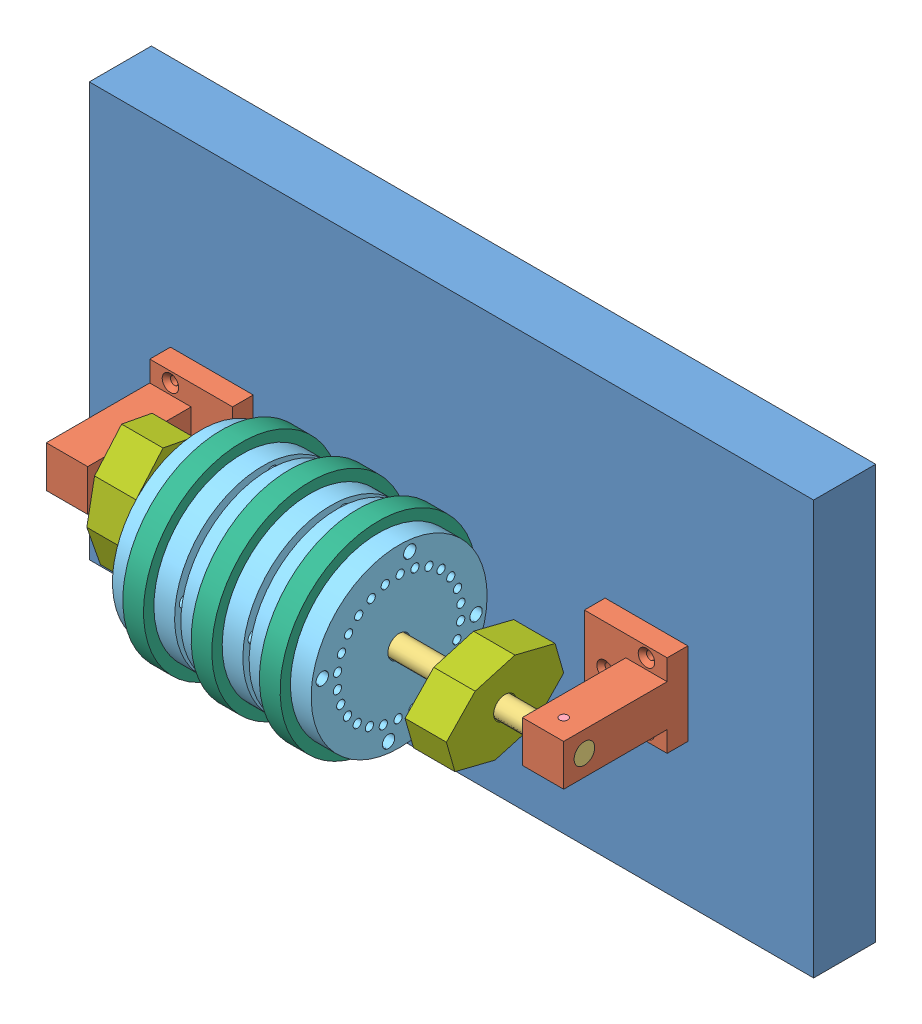
SolidWorks assembly assemblage total, configuration Défaut. Lengths in mm.
Overall size (68.97 20 13.46).
17 component instances, 7 part files, 30 mates.
Components (placement in the parent):
- socle-1: socle [Défaut] at (-0.5194 -1.8116 67.4682) size (68.97 20 3)
- support-1: support [Défaut] at (-14.5104 1.1426 70.4682) x (0 1 0) z (1 0 0) size (4 6 4)
- support-2: support [Défaut] at (10.4896 -4.7659 70.4682) x (0 -1 0) z (-1 0 0) size (4 6 4)
- tige 1cd-2: tige 1cd [Défaut] at (-14.5104 -1.8116 75.4682) x (0 0 -1) z (1 0 0) size (1 1 25)
- vis solid tige-3: vis solid tige [Défaut] at (-13.5104 -2.8116 75.4682) x (-0.663281 0 -0.74837) z (0 1 0) size (0.4 0.4 1)
- vis solid tige-4: vis solid tige [Défaut] at (9.4896 -1.8116 75.4682) x (1 0 0) z (0 1 0) size (0.4 0.4 1)
- rotor-1: rotor [Défaut] at (-0.4605 -1.8116 75.4682) x (0 0.136597 0.990627) z (0 -0.990627 0.136597) size (8.5 1 8.5)
- rotor-2: rotor [Défaut] at (-3.7605 -1.8116 75.4682) x (0 0.163961 0.986467) z (0 -0.986467 0.163961) size (8.5 1 8.5)
- rotor-3: rotor [Défaut] at (-7.0605 -1.8116 75.4682) x (0 0.992267 -0.124123) z (0 0.124123 0.992267) size (8.5 1 8.5)
- rotor-4: rotor [Défaut] at (-5.0605 -1.8116 75.4682) x (0 -0.124123 -0.992267) z (0 0.992267 -0.124123) size (8.5 1 8.5)
- rotor-5: rotor [Défaut] at (-1.7605 -1.8116 75.4682) x (0 -0.163961 -0.986467) z (0 0.986467 -0.163961) size (8.5 1 8.5)
- rotor-6: rotor [Défaut] at (1.5395 -1.8116 75.4682) x (0 0.990627 -0.136597) z (0 0.136597 0.990627) size (8.5 1 8.5)
- pignon sans pigon-1: pignon sans pigon [Défaut] at (-0.4605 -1.8116 75.4682) x (0 0.136597 0.990627) z (1 0 0) size (9.5 9.5 1)
- pignon sans pigon-2: pignon sans pigon [Défaut] at (-3.7605 -1.8116 75.4682) x (0 -0.986467 0.163961) z (1 0 0) size (9.5 9.5 1)
- pignon sans pigon-3: pignon sans pigon [Défaut] at (-7.0605 -1.8116 75.4682) x (0 0.124123 0.992267) z (1 0 0) size (9.5 9.5 1)
- stoppeur-1: stoppeur [Défaut] at (4.6558 -1.5903 74.8697) x (0 -0.275103 0.961415) z (1 0 0) size (5.46 3.5 2)
- stoppeur-2: stoppeur [Défaut] at (-11.645 -1.1775 75.3963) x (0 -0.982295 0.187342) z (1 0 0) size (5.46 3.5 2)
Mates (geometry in assembly coordinates):
- Coïncidente1: coincident anti-aligned: line of socle-1 through (-5.0901 -1.8116 70.4682) axis (-1 0 0); line of support-1 through (-14.5104 -1.8116 70.4682) axis (1 0 0)
- Coïncidente2: coincident anti-aligned: plane of socle-1 through (-0.5194 -1.8116 70.4682) normal (0 0 1); plane of support-1 through (-12.5104 -3.8116 70.4682) normal (0 0 -1)
- Coïncidente3: coincident anti-aligned: line of socle-1 through (-36.7229 -1.8116 70.4682) axis (1 0 0); line of support-2 through (10.4896 -1.8116 70.4682) axis (-1 0 0)
- Coïncidente4: coincident anti-aligned: plane of socle-1 through (-0.5194 -1.8116 70.4682) normal (0 0 1); plane of support-2 through (8.4896 0.1884 70.4682) normal (0 0 -1)
- Coaxiale6: concentric anti-aligned: cylinder of support-1 through (-14.5104 -1.8116 75.4682) axis (1 0 0) radius 0.5; cylinder of tige 1cd-2 through (10.4896 -1.8116 75.4682) axis (-1 0 0) radius 0.5
- Coaxiale7: concentric anti-aligned: cylinder of tige 1cd-2 through (-13.5104 -2.8116 75.4682) axis (0 1 0) radius 0.2; cylinder of vis solid tige-3 through (-13.5104 -1.8116 75.4682) axis (0 -1 0) radius 0.2
- Coïncidente7: coincident anti-aligned: plane of tige 1cd-2 through (-13.5104 -1.8116 75.4682) normal (0 -1 0); plane of vis solid tige-3 through (-13.5104 -1.8116 75.4682) normal (0 1 0)
- Coaxiale8: concentric aligned: cylinder of tige 1cd-2 through (9.4896 -0.8116 75.4682) axis (0 -1 0) radius 0.2; cylinder of vis solid tige-4 through (9.4896 -0.8116 75.4682) axis (0 -1 0) radius 0.2
- Coïncidente8: coincident anti-aligned: plane of tige 1cd-2 through (9.4896 -1.8116 75.4682) normal (0 1 0); plane of vis solid tige-4 through (9.4896 -1.8116 75.4682) normal (0 -1 0)
- Coaxiale9: concentric aligned: cylinder of support-1 through (-13.5104 -1.8116 75.4682) axis (0 -1 0) radius 0.2; cylinder of vis solid tige-3 through (-13.5104 -1.8116 75.4682) axis (0 -1 0) radius 0.2
- Coaxiale10: concentric anti-aligned: cylinder of support-2 through (9.4896 -1.8116 75.4682) axis (0 1 0) radius 0.2; cylinder of vis solid tige-4 through (9.4896 -0.8116 75.4682) axis (0 -1 0) radius 0.2
- Coaxiale11: concentric anti-aligned: cylinder of tige 1cd-2 through (10.4896 -1.8116 75.4682) axis (-1 0 0) radius 0.5; cylinder of rotor-2 through (-4.7605 -1.8116 75.4682) axis (1 0 0) radius 0.55
- Coaxiale12: concentric anti-aligned: cylinder of tige 1cd-2 through (10.4896 -1.8116 75.4682) axis (-1 0 0) radius 0.5; cylinder of rotor-1 through (-1.4605 -1.8116 75.4682) axis (1 0 0) radius 0.55
- Coaxiale13: concentric anti-aligned: cylinder of tige 1cd-2 through (10.4896 -1.8116 75.4682) axis (-1 0 0) radius 0.5; cylinder of rotor-3 through (-8.0605 -1.8116 75.4682) axis (1 0 0) radius 0.55
- Coaxiale14: concentric anti-aligned: cylinder of tige 1cd-2 through (10.4896 -1.8116 75.4682) axis (-1 0 0) radius 0.5; cylinder of rotor-4 through (-6.0605 -1.8116 75.4682) axis (1 0 0) radius 0.55
- Coaxiale15: concentric anti-aligned: cylinder of tige 1cd-2 through (10.4896 -1.8116 75.4682) axis (-1 0 0) radius 0.5; cylinder of rotor-5 through (-2.7605 -1.8116 75.4682) axis (1 0 0) radius 0.55
- Coaxiale16: concentric anti-aligned: cylinder of tige 1cd-2 through (10.4896 -1.8116 75.4682) axis (-1 0 0) radius 0.5; cylinder of rotor-6 through (0.5395 -1.8116 75.4682) axis (1 0 0) radius 0.55
- Coïncidente9: coincident anti-aligned: circle of rotor-6; circle of pignon sans pigon-1
- Coïncidente12: coincident anti-aligned: circle of rotor-6; circle of pignon sans pigon-1
- Coïncidente13: coincident anti-aligned: circle of rotor-1; circle of pignon sans pigon-1
- Coïncidente14: coincident anti-aligned: circle of rotor-5; circle of pignon sans pigon-2
- Coïncidente15: coincident anti-aligned: circle of rotor-5; circle of pignon sans pigon-2
- Coïncidente16: coincident anti-aligned: circle of rotor-2; circle of pignon sans pigon-2
- Coïncidente18: coincident anti-aligned: circle of rotor-4; circle of pignon sans pigon-3
- Coïncidente19: coincident anti-aligned: circle of rotor-4; circle of pignon sans pigon-3
- Coïncidente20: coincident anti-aligned: circle of rotor-3; circle of pignon sans pigon-3
- Coaxiale17: concentric anti-aligned: cylinder of tige 1cd-2 through (10.4896 -1.8116 75.4682) axis (-1 0 0) radius 0.5; cylinder of stoppeur-2 through (-11.645 -1.8116 75.4682) axis (1 0 0) radius 0.5522
- Coaxiale18: concentric anti-aligned: cylinder of tige 1cd-2 through (10.4896 -1.8116 75.4682) axis (-1 0 0) radius 0.5; cylinder of stoppeur-1 through (4.6558 -1.8116 75.4682) axis (1 0 0) radius 0.5522
- Distance1: distance = 0.3 mm anti-aligned: plane of rotor-1 through (-1.4605 -1.8116 75.4682) normal (-1 0 0); plane of rotor-5 through (-1.7605 -1.8116 75.4682) normal (1 0 0)
- Distance2: distance = 0.3 mm anti-aligned: plane of rotor-2 through (-4.7605 -1.8116 75.4682) normal (-1 0 0); plane of rotor-4 through (-5.0605 -1.8116 75.4682) normal (1 0 0)
